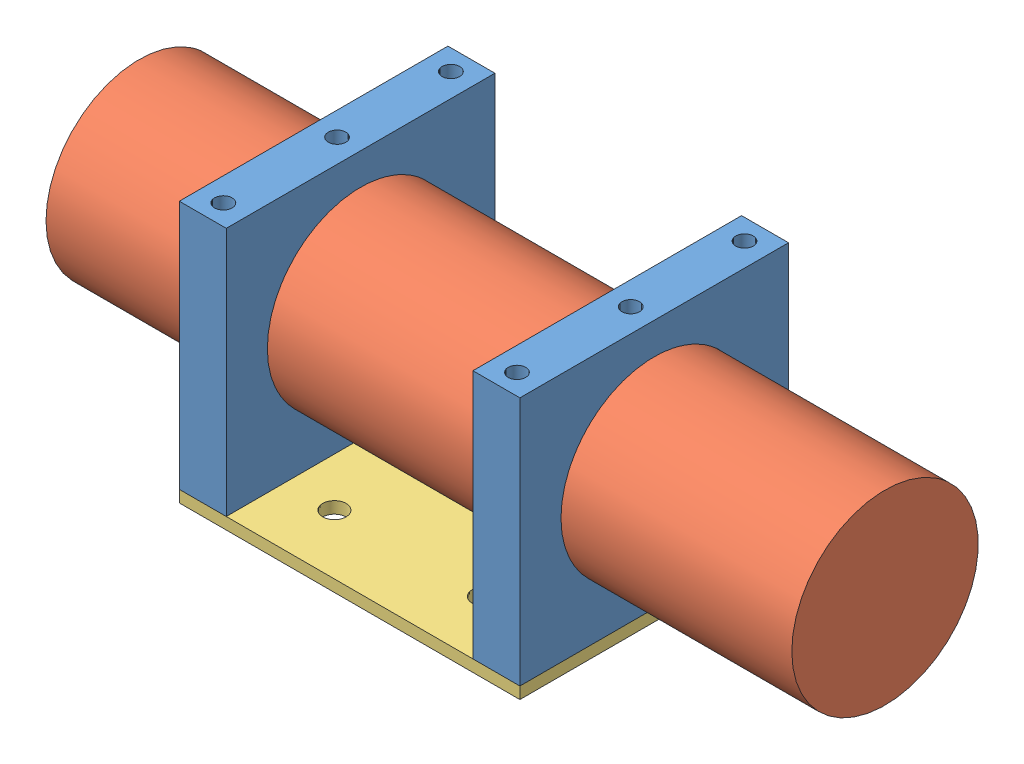
SolidWorks assembly motor_mount_assembly_james, configuration Default. Lengths in mm.
Overall size (127 45.49 45.75).
4 component instances, 3 part files, 5 mates.
Components (placement in the parent):
- clamp-1: clamp [Default] at (20.4818 -1.5894 -13.8682) size (8 42.5 45.75)
- clamp-2: clamp [Default] at (-29.5182 -1.5894 -13.8682) size (8 42.5 45.75)
- tube-2: tube [Default] at (-63.2146 19.6606 -13.8682) x (0 0.60318 0.797605) z (0 0.797605 -0.60318) size (31.75 127 31.75)
- Motor_Mount_Base_6061T6-2: Motor_Mount_Base_6061T6 [Default] at (-4.5182 -3.5894 -13.8682) size (58 2 45.75)
Mates (geometry in assembly coordinates):
- Concentric8: concentric anti-aligned: cylinder of clamp-1 through (-18.0177 19.6606 -13.8682) axis (1 0 0) radius 15.875; cylinder of tube-2 through (63.7854 19.6606 -13.8682) axis (-1 0 0) radius 15.875
- Concentric9: concentric anti-aligned: cylinder of clamp-2 through (-68.0177 19.6606 -13.8682) axis (1 0 0) radius 15.875; cylinder of tube-2 through (63.7854 19.6606 -13.8682) axis (-1 0 0) radius 15.875
- Concentric10: concentric anti-aligned: cylinder of clamp-2 through (-63.4995 26.25 0) axis (1 0 0) radius 15.875; cylinder of tube-2 through (130.5817 26.25 0) axis (-1 0 0) radius 15.875
- Coincident22: coincident anti-aligned: circle of clamp-1; circle of Motor_Mount_Base_6061T6-2
- Coincident23: coincident anti-aligned: circle of clamp-2; circle of Motor_Mount_Base_6061T6-2
